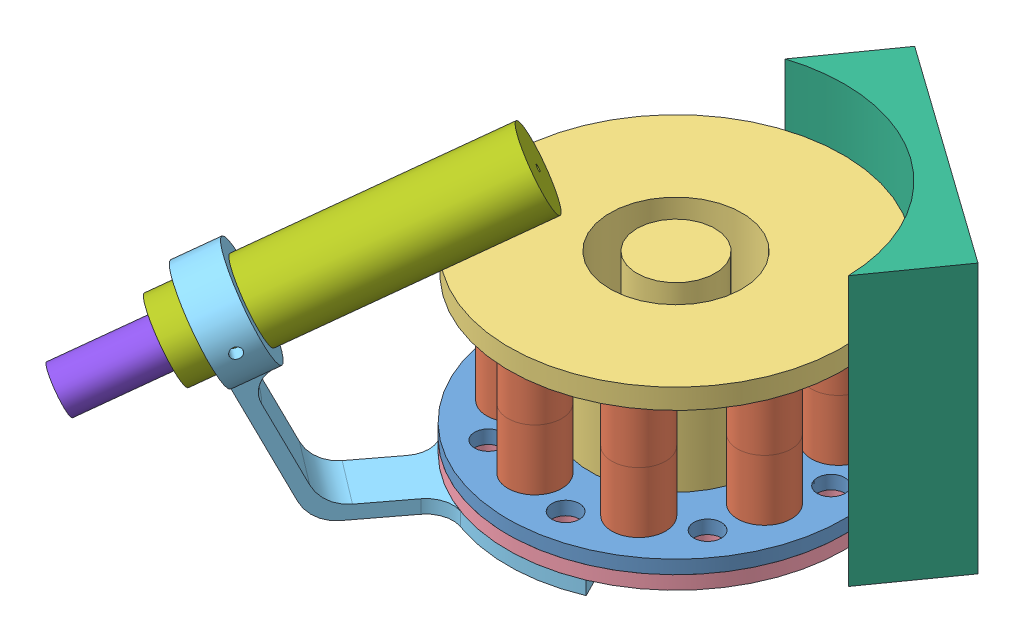
SolidWorks assembly Aseembly, configuration Default. Lengths in mm.
Overall size (83.54 59.24 90.91).
26 component instances, 9 part files, 27 mates.
Components (placement in the parent):
- base_plate-3: base_plate [Default] at (-36.646 29.2594 17.7308) size (50 8 50)
- magnet_cyclo180-17: magnet_cyclo180 [Default] at (-36.646 30.2594 17.7308) x (-0.894675 0 0.446717) z (-0.446717 0 -0.894675) size (8 10 8)
- magnet_cyclo180-18: magnet_cyclo180 [Default] at (-27.3545 30.2594 32.5604) x (0.951763 0 -0.306835) z (0.306835 0 0.951763) size (8 10 8)
- magnet_cyclo180-19: magnet_cyclo180 [Default] at (-40.562 30.2594 34.787) x (0.889963 0 0.456033) z (-0.456033 0 0.889963) size (8 10 8)
- magnet_cyclo180-20: magnet_cyclo180 [Default] at (-51.4756 30.2594 27.0223) x (0.306835 0 0.951763) z (-0.951763 0 0.306835) size (8 10 8)
- magnet_cyclo180-21: magnet_cyclo180 [Default] at (-53.7022 30.2594 13.8147) x (-0.456033 0 0.889963) z (-0.889963 0 -0.456033) size (8 10 8)
- magnet_cyclo180-22: magnet_cyclo180 [Default] at (-45.9375 30.2594 2.9011) x (-0.951763 0 0.306835) z (-0.306835 0 -0.951763) size (8 10 8)
- magnet_cyclo180-23: magnet_cyclo180 [Default] at (-32.7299 30.2594 0.6746) x (-0.889963 0 -0.456033) z (0.456033 0 -0.889963) size (8 10 8)
- magnet_cyclo180-24: magnet_cyclo180 [Default] at (-21.8164 30.2594 8.4393) x (-0.306835 0 -0.951763) z (0.951763 0 -0.306835) size (8 10 8)
- magnet_cyclo180-25: magnet_cyclo180 [Default] at (-19.5898 30.2594 21.6468) x (0.456033 0 -0.889963) z (0.889963 0 0.456033) size (8 10 8)
- insulator-2: insulator [Default] at (-36.646 31.2594 17.7308) x (0.874558 0 0.48492) z (0 1 0) size (49.6 49.6 22)
- magnet_cyclo180-26: magnet_cyclo180 [Default] at (-51.4756 40.2594 27.0223) x (0.306835 0 0.951763) z (-0.951763 0 0.306835) size (8 10 8)
- magnet_cyclo180-27: magnet_cyclo180 [Default] at (-36.646 40.2594 17.7308) x (-0.894675 0 0.446717) z (-0.446717 0 -0.894675) size (8 10 8)
- magnet_cyclo180-28: magnet_cyclo180 [Default] at (-53.7022 40.2594 13.8147) x (-0.456033 0 0.889963) z (-0.889963 0 -0.456033) size (8 10 8)
- magnet_cyclo180-29: magnet_cyclo180 [Default] at (-45.9375 40.2594 2.9011) x (-0.951763 0 0.306835) z (-0.306835 0 -0.951763) size (8 10 8)
- magnet_cyclo180-30: magnet_cyclo180 [Default] at (-32.7299 40.2594 0.6746) x (-0.889963 0 -0.456033) z (0.456033 0 -0.889963) size (8 10 8)
- magnet_cyclo180-31: magnet_cyclo180 [Default] at (-21.8164 40.2594 8.4393) x (-0.306835 0 -0.951763) z (0.951763 0 -0.306835) size (8 10 8)
- magnet_cyclo180-32: magnet_cyclo180 [Default] at (-19.5898 40.2594 21.6468) x (0.456033 0 -0.889963) z (0.889963 0 0.456033) size (8 10 8)
- magnet_cyclo180-33: magnet_cyclo180 [Default] at (-27.3545 40.2594 32.5604) x (0.951763 0 -0.306835) z (0.306835 0 0.951763) size (8 10 8)
- magnet_cyclo180-34: magnet_cyclo180 [Default] at (-40.562 40.2594 34.787) x (0.889963 0 0.456033) z (-0.456033 0 0.889963) size (8 10 8)
- base_plate_insulating-2: base_plate_insulating [Default] at (-36.646 29.2594 17.7308) x (0.225197 0 -0.974313) z (-0.974313 0 -0.225197) size (50 2 50)
- mounting_bracket-2: mounting_bracket [Default] at (-62.4124 49.9171 59.3042) x (0.255584 -0.906308 -0.336576) z (0.548101 0.422618 -0.721789) size (47.08 43.47 29.39)
- stand-1: stand [Default] at (-36.646 22.2594 17.7308) x (0.814816 0 0.579719) z (-0.579719 0 0.814816) size (40 40 13.81)
- Retainer body 1.4-1: Retainer body 1.4 [Heaterless] at (12.071 297.1685 -153.6958) x (-0.548101 -0.422618 0.721789) z (-0.602179 -0.399525 -0.691202) size (43.5 11 11)
- Cathode tube 1.3-1: Cathode tube 1.3 [Default] at (-52.4436 60.06 39.5622) x (0.548101 0.422618 -0.721789) z (0.721789 0.197042 0.663472) size (53.5 6.5 6.5)
- alumina_insulator-2: alumina_insulator [Default] at (-63.4056 51.6076 53.998) x (0.565751 0.448273 0.692082) z (-0.548101 -0.422618 0.721789) size (9 9 10)
Mates (geometry in assembly coordinates):
- Concentric11: concentric aligned: circle of base_plate-3; circle of magnet_cyclo180-17
- Coincident19: coincident anti-aligned: plane of base_plate-3 through (-36.646 30.2594 17.7308) normal (0 1 0); plane of magnet_cyclo180-17 through (-36.646 30.2594 17.7308) normal (0 -1 0)
- Concentric12: concentric aligned: circle of base_plate-3; circle of magnet_cyclo180-18
- Coincident22: coincident anti-aligned: plane of base_plate-3 through (-27.3545 30.2594 32.5604) normal (0 1 0); plane of magnet_cyclo180-18 through (-27.3545 30.2594 32.5604) normal (0 -1 0)
- Coincident23: coincident anti-aligned: plane of base_plate-3 through (-36.646 31.2594 17.7308) normal (0 1 0); plane of insulator-2 through (-34.7063 31.2594 14.2325) normal (0 -1 0)
- Concentric13: concentric aligned: cylinder of base_plate-3 through (-38.7124 29.2594 10.521) axis (0 1 0) radius 1.05; circle of insulator-2
- Coincident28: coincident aligned: plane of base_plate-3 through (-36.646 29.2594 17.7308) normal (0 -1 0); plane of base_plate_insulating-1 through (-36.646 29.2594 17.7308) normal (0 -1 0)
- Coincident30: coincident anti-aligned: plane of base_plate-3 through (-36.646 29.2594 17.7308) normal (0 -1 0); plane of base_plate_insulating-2 through (-36.646 29.2594 17.7308) normal (0 1 0)
- Concentric19: concentric anti-aligned: circle of insulator-2; cylinder of base_plate_insulating-2 through (-40.2829 29.2594 24.29) axis (0 -1 0) radius 1.05
- Coincident32: coincident anti-aligned: plane of base_plate_insulating-2 through (-36.646 27.2594 17.7308) normal (0 -1 0); plane of mounting_bracket-2 through (-62.394 27.2594 46.0517) normal (0 1 0)
- Coincident33: coincident anti-aligned: plane of base_plate_insulating-2 through (-36.646 27.2594 17.7308) normal (0 -1 0); plane of mounting_bracket-2 through (-62.394 27.2594 46.0517) normal (0 1 0)
- Concentric25: concentric anti-aligned: cylinder of base_plate_insulating-2 through (-36.646 27.2594 17.7308) axis (0 1 0) radius 25; cylinder of stand-1 through (-36.646 62.2594 17.7308) axis (0 -1 0) radius 25
- Coincident36: coincident anti-aligned: plane of base_plate_insulating-2 through (-36.646 27.2594 17.7308) normal (0 -1 0); plane of stand-1 through (-36.646 27.2594 17.7308) normal (0 1 0)
- Coincident37: coincident anti-aligned: circle of base_plate_insulating-2; circle of stand-1
- Concentric26: concentric anti-aligned: circle of base_plate_insulating-2; circle of mounting_bracket-2
- Concentric27: concentric anti-aligned: circle of base_plate_insulating-2; cylinder of mounting_bracket-2 through (-33.3212 37.2594 37.4525) axis (0 -1 0) radius 2.05
- Concentric30: concentric aligned: circle of base_plate-3; circle of base_plate_insulating-2
- Concentric33: concentric aligned: circle of mounting_bracket-2; circle of Retainer body 1.4-1
- Distance1: distance = 4 mm aligned: plane of mounting_bracket-2 through (-69.8798 49.0719 55.9097) normal (-0.548101 -0.422618 0.721789); plane of Retainer body 1.4-1 through (-155.1317 168.2453 66.492) normal (-0.548101 -0.422618 0.721789)
- Concentric34: concentric aligned: circle of Retainer body 1.4-1; circle of Cathode tube 1.3-1
- Distance2: distance = 1 mm anti-aligned: plane of Cathode tube 1.3-1 through (-46.6258 65.1511 31.7211) normal (0.548101 0.422618 -0.721789); plane of Retainer body 1.4-1 through (-132.1115 185.9953 36.1769) normal (-0.548101 -0.422618 0.721789)
- InPlace1: in place: plane of Retainer body 1.4-1 through (-155.1317 168.2453 66.492) normal (-0.548101 -0.422618 0.721789); plane of ? through (-33.937 -26.1675 44.6914) normal (-0.548101 -0.422618 0.721789); moOrthogonalPlaneRef_w of Retainer body 1.4-1 through (-155.1317 168.2453 66.492) normal (-0.548101 -0.422618 0.721789); plane of ? through (-33.937 -26.1675 44.6914) normal (0 0.862958 0.505275); plane of Retainer body 1.4-1 through (-155.1317 168.2453 66.492) normal (-0.548101 -0.422618 0.721789); plane of ? through (-33.937 -26.1675 44.6914) normal (0.836412 -0.276942 0.472988); plane of Retainer body 1.4-1 through (-155.1317 168.2453 66.492) normal (-0.548101 -0.422618 0.721789); unknown of ?
- Coincident45: coincident aligned: plane of Retainer body 1.4-1; plane of ?
- Coincident46: coincident aligned: plane of Retainer body 1.4-1 through (-155.1317 168.2453 66.492) normal (-0.580487 0.813495 0.035512); plane of Part1^Aseembly-1 through (-155.1317 168.2453 66.492) normal (-0.580487 0.813495 0.035512)
- Coincident47: coincident anti-aligned: plane of Retainer body 1.4-1 through (-155.1317 168.2453 66.492) normal (-0.602179 -0.399525 -0.691202); plane of Part1^Aseembly-1 through (-155.1317 168.2453 66.492) normal (0.602179 0.399525 0.691202)
- Concentric35: concentric aligned: circle of Retainer body 1.4-1; cylinder of alumina_insulator-2 through (-68.8866 47.3814 61.2159) axis (0.548101 0.422618 -0.721789) radius 3
- Coincident48: coincident anti-aligned: plane of Retainer body 1.4-1 through (-149.6507 172.4715 59.2741) normal (-0.548101 -0.422618 0.721789); plane of alumina_insulator-2 through (-63.4056 51.6076 53.998) normal (0.548101 0.422618 -0.721789)
